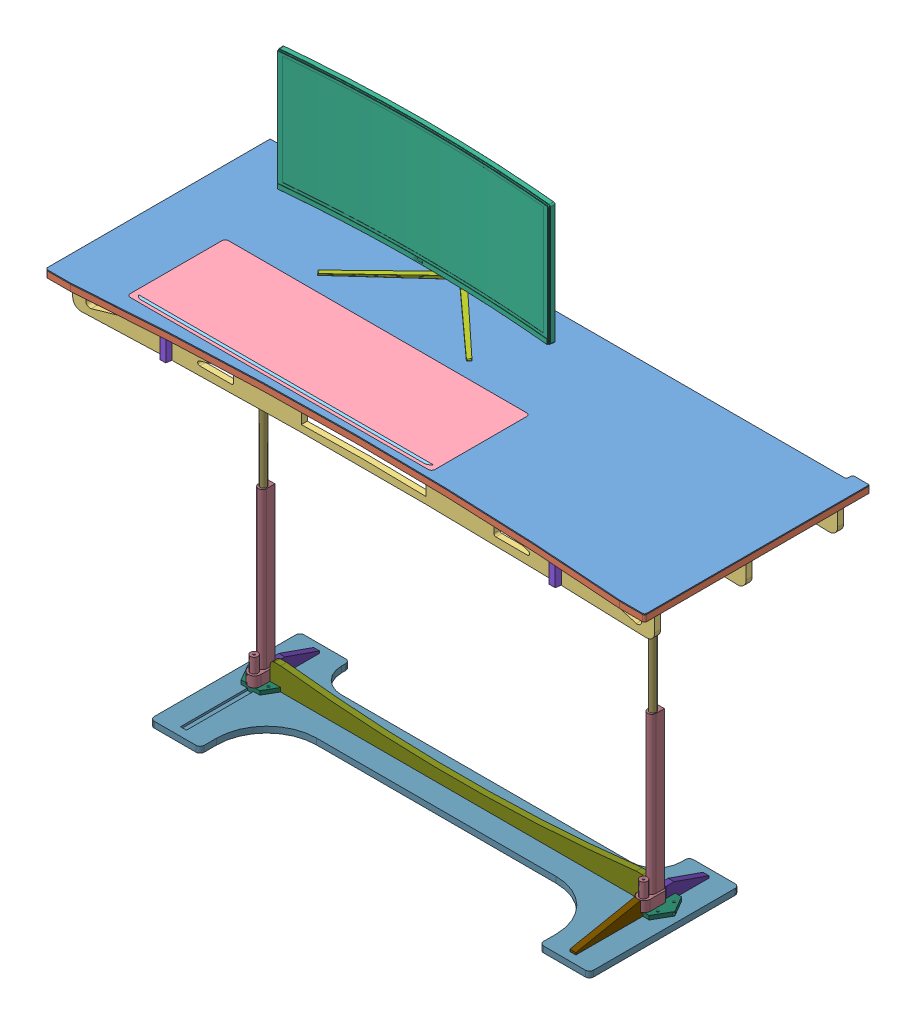
SolidWorks assembly Table2, configuration Default. Lengths in mm.
Overall size (1828.8 1607.28 685.8).
41 component instances, 18 part files, 106 mates.
Components (placement in the parent):
- PlasticDeskSurface-1: PlasticDeskSurface [Default] at (787.903 1218.7548 1407.4946) size (1828.8 3.17 685.8)
- WoodenDeskSurface2-1: WoodenDeskSurface2 [Default] at (787.903 1199.7048 1407.4946) size (1828.8 19.05 685.8)
- TableSupport-1: TableSupport [Default] at (787.268 1155.2548 1683.7196) size (1776.73 100.55 18.29)
- TableSupport-2: TableSupport [Default] at (787.268 1155.2548 1404.3196) size (1776.73 100.55 18.29)
- TableSupport-3: TableSupport [Default] at (787.268 1155.2548 1124.9196) size (1776.73 100.55 18.29)
- CorsairMM200-1: CorsairMM200 [Default] at (533.903 1218.9298 1547.1946) size (930 3 300)
- CorsairMM200Part2-1: CorsairMM200Part2 [Default] at (533.903 1218.9298 1547.1946) size (900 3 10)
- 34monitor-1: 34monitor [Default] at (533.8994 1324.5298 1285.8011) size (858.27 521.12 391.75)
  - Monitor^34monitor-1: Monitor^34monitor [Default] at origin size (858.27 431.15 192.74) (virtual)
  - Stand^34monitor-1: Stand^34monitor [Default] at origin size (475.11 329.67 391.69) (virtual)
- SupportSupport-4: SupportSupport [Default] at (192.8884 1149.35 1407.1136) x (0 0 -1) z (-1 0 0) size (628.27 139.7 18.29)
- SupportSupport-5: SupportSupport [Default] at (1381.6477 1149.35 1407.1136) x (0 0 -1) z (-1 0 0) size (628.27 139.7 18.29)
- LinearActuatorTopSupport-1: LinearActuatorTopSupport [Default] at (192.8884 1060.45 1404.3196) x (0 0 -1) z (-1 0 0) size (152.4 95.25 32.77)
- LinearActuatorTopSupport-2: LinearActuatorTopSupport [Default] at (1381.6477 1060.45 1404.3196) x (0 0 -1) z (-1 0 0) size (152.4 95.25 32.77)
- hex bolt_ai-1: hex bolt_ai [HBOLT 0.2500-20x1.5x0.75-C] at (172.2382 1079.5 1404.3196) x (1 0 0) z (0 0.5 0.866025) size (42.88 12.85 11.13)
- hex bolt_ai-2: hex bolt_ai [HBOLT 0.2500-20x1.5x0.75-C] at (1402.2979 1079.5 1458.2946) x (-1 0 0) z (0 1 0) size (42.88 12.85 11.13)
- hex bolt_ai-3: hex bolt_ai [HBOLT 0.2500-20x1.5x0.75-C] at (172.2382 1079.5 1458.2946) x (1 0 0) z (0 0.5 0.866025) size (42.88 12.85 11.13)
- hex bolt_ai-4: hex bolt_ai [HBOLT 0.2500-20x1.5x0.75-C] at (172.2382 1079.5 1350.3446) x (1 0 0) z (0 0.5 0.866025) size (42.88 12.85 11.13)
- hex bolt_ai-5: hex bolt_ai [HBOLT 0.2500-20x1.5x0.75-C] at (1402.2979 1079.5 1404.3196) x (-1 0 0) z (0 1 0) size (42.88 12.85 11.13)
- hex bolt_ai-6: hex bolt_ai [HBOLT 0.2500-20x1.5x0.75-C] at (1402.2979 1079.5 1350.3446) x (-1 0 0) z (0 1 0) size (42.88 12.85 11.13)
- hex nut_ai-1: hex nut_ai [HNUT 0.2500-20-D-C] at (214.5038 1079.5 1350.3446) x (0 0 -1) z (1 0 0) size (11.11 12.83 5.74)
- hex nut_ai-2: hex nut_ai [HNUT 0.2500-20-D-C] at (1360.0323 1079.5 1350.3446) x (0 0 1) z (-1 0 0) size (11.11 12.83 5.74)
- hex nut_ai-3: hex nut_ai [HNUT 0.2500-20-D-C] at (1360.0323 1079.5 1404.3196) x (0 0 1) z (-1 0 0) size (11.11 12.83 5.74)
- hex nut_ai-4: hex nut_ai [HNUT 0.2500-20-D-C] at (1360.0323 1079.5 1458.2946) x (0 0 1) z (-1 0 0) size (11.11 12.83 5.74)
- hex nut_ai-5: hex nut_ai [HNUT 0.2500-20-D-C] at (214.5038 1079.5 1458.2946) x (0 0 -1) z (1 0 0) size (11.11 12.83 5.74)
- hex nut_ai-6: hex nut_ai [HNUT 0.2500-20-D-C] at (214.5038 1079.5 1404.3196) x (0 0 -1) z (1 0 0) size (11.11 12.83 5.74)
- LinearActuatorRod-1: LinearActuatorRod [Default] at (192.8884 524.51 1404.3196) size (20.07 527.05 20.07)
- hex bolt_ai-12: hex bolt_ai [HBOLT 0.3125-18x1.5x0.875-C] at (171.0444 1041.4 1404.3196) size (44.07 14.66 12.7)
- hex bolt_ai-13: hex bolt_ai [HBOLT 0.3125-18x1.5x0.875-C] at (1359.8037 1041.4 1404.3196) size (44.07 14.66 12.7)
- LinearActuatorRod-2: LinearActuatorRod [Default] at (1381.6477 524.51 1404.3196) size (20.07 527.05 20.07)
- hex nut_ai-7: hex nut_ai [HNUT 0.3125-18-D-C] at (1404.4569 1041.4 1404.3196) x (0 0 -1) z (1 0 0) size (12.7 14.66 6.93)
- hex nut_ai-8: hex nut_ai [HNUT 0.3125-18-D-C] at (215.6976 1041.4 1404.3196) x (0 0 -1) z (1 0 0) size (12.7 14.66 6.93)
- ActuatorBottom-1: ActuatorBottom [Default] at (192.8884 127 1394.7946) size (38.09 527.05 75.55)
- ActuatorBottom-2: ActuatorBottom [Default] at (1381.6477 127 1394.7946) size (38.09 527.05 75.55)
- NewBase1-1: NewBase1 [Default] at (787.2484 96.774 1688.4069) size (1341.12 18.29 457.2)
- NewBase2-1: NewBase2 [Default] at (192.8884 108.712 1394.7946) size (109.02 18.29 98.99)
- NewBase2-2: NewBase2 [Default] at (1381.6084 108.712 1394.7946) x (-1 0 0) z (0 0 -1) size (109.02 18.29 98.99)
- NewBase3-1: NewBase3 [Default] at (787.3031 108.712 1394.7946) size (1148.59 75.44 18.29)
- NewBase4-1: NewBase4 [Default] at (1381.6084 108.712 1345.3013) x (0 0 -1) z (1 0 0) size (131.44 50.04 18.29)
- NewBase4-2: NewBase4 [Default] at (192.8884 108.712 1345.3013) x (0 0 -1) z (1 0 0) size (131.44 50.04 18.29)
- NewBase5-2: NewBase5 [Default] at (1390.7524 108.712 1444.288) x (0 0 1) z (-1 0 0) size (204.47 51.95 18.29)
Mates (geometry in assembly coordinates):
- Coincident4: coincident anti-aligned: plane of PlasticDeskSurface-1 through (-120.147 1218.7548 1744.0446) normal (0 -1 0); plane of WoodenDeskSurface2-1 through (-120.147 1218.7548 1744.0446) normal (0 1 0)
- Coincident5: coincident aligned: plane of PlasticDeskSurface-1 through (1702.303 1221.9298 1744.0446) normal (1 0 0); plane of WoodenDeskSurface2-1 through (1702.303 1218.7548 1744.0446) normal (1 0 0)
- Coincident6: coincident aligned: plane of PlasticDeskSurface-1 through (-69.347 1218.7548 1083.6446) normal (0 0 -1); plane of WoodenDeskSurface2-1 through (-69.347 1199.7048 1083.6446) normal (0 0 -1)
- Coincident7: coincident anti-aligned: plane of WoodenDeskSurface2-1 through (1676.903 1206.0548 1692.8636) normal (0 0 -1); plane of TableSupport-1 through (787.268 -20467.2606 1692.8636) normal (0 0 1)
- Coincident8: coincident anti-aligned: plane of WoodenDeskSurface2-1 through (-101.097 1206.0548 1674.5756) normal (1 0 0); plane of TableSupport-1 through (-101.097 1206.0548 1692.8636) normal (-1 0 0)
- Coincident9: coincident anti-aligned: plane of WoodenDeskSurface2-1 through (787.903 1206.0548 1407.4946) normal (0 -1 0); plane of TableSupport-1 through (-101.097 1206.0548 1692.8636) normal (0 1 0)
- Coincident10: coincident anti-aligned: plane of WoodenDeskSurface2-1 through (1676.903 1206.0548 1413.4636) normal (0 0 -1); plane of TableSupport-2 through (787.268 -20467.2606 1413.4636) normal (0 0 1)
- Coincident11: coincident anti-aligned: plane of WoodenDeskSurface2-1 through (-101.097 1206.0548 1413.4636) normal (1 0 0); plane of TableSupport-2 through (-101.097 1206.0548 1413.4636) normal (-1 0 0)
- Coincident12: coincident anti-aligned: plane of WoodenDeskSurface2-1 through (787.903 1206.0548 1407.4946) normal (0 -1 0); plane of TableSupport-2 through (-101.097 1206.0548 1413.4636) normal (0 1 0)
- Coincident13: coincident anti-aligned: plane of WoodenDeskSurface2-1 through (-101.097 1206.0548 1115.7756) normal (1 0 0); plane of TableSupport-3 through (-101.097 1206.0548 1134.0636) normal (-1 0 0)
- Coincident14: coincident anti-aligned: plane of WoodenDeskSurface2-1 through (1676.903 1206.0548 1115.7756) normal (0 0 1); plane of TableSupport-3 through (787.268 -20467.2606 1115.7756) normal (0 0 -1)
- Coincident15: coincident anti-aligned: plane of WoodenDeskSurface2-1 through (787.903 1206.0548 1407.4946) normal (0 -1 0); plane of TableSupport-3 through (-101.097 1206.0548 1134.0636) normal (0 1 0)
- Parallel1: parallel aligned: plane of TableSupport-1 through (787.268 -20467.2606 1692.8636) normal (0 0 1); plane of assembly through (0 0 0) normal (0 0 1)
- Parallel2: parallel anti-aligned: plane of WoodenDeskSurface2-1 through (-120.147 1199.7048 1744.0446) normal (0 -1 0); plane of assembly through (0 0 0) normal (0 1 0)
- Coincident24: coincident anti-aligned: plane of PlasticDeskSurface-1 through (78.903 1218.9298 1687.1946) normal (0 1 0); plane of CorsairMM200-1 through (78.903 1218.9298 1687.1946) normal (0 -1 0)
- Coincident25: coincident anti-aligned: plane of PlasticDeskSurface-1 through (78.903 1218.9298 1697.1946) normal (0 0 -1); plane of CorsairMM200-1 through (78.903 1221.9298 1697.1946) normal (0 0 1)
- Coincident26: coincident anti-aligned: plane of PlasticDeskSurface-1 through (998.903 1218.9298 1687.1946) normal (-1 0 0); plane of CorsairMM200-1 through (998.903 1221.9298 1687.1946) normal (1 0 0)
- Coincident28: coincident anti-aligned: plane of CorsairMM200-1 through (100.2376 1218.9298 1687.1946) normal (0 0 -1); plane of CorsairMM200Part2-1 through (100.2376 1221.9298 1687.1946) normal (0 0 1)
- Concentric1: concentric anti-aligned: cylinder of CorsairMM200-1 through (964.6509 1218.9298 1664.088) axis (0 1 0) radius 23.29; cylinder of CorsairMM200Part2-1 through (964.6509 1221.9298 1664.088) axis (0 -1 0) radius 23.29
- Coincident29: coincident anti-aligned: plane of PlasticDeskSurface-1 through (78.903 1218.9298 1687.1946) normal (0 1 0); plane of CorsairMM200Part2-1 through (103.1552 1218.9298 1664.088) normal (0 -1 0)
- Coincident30: coincident anti-aligned: plane of PlasticDeskSurface-1 through (-120.147 1221.9298 1744.0446) normal (0 1 0); plane of 34monitor-1/Stand^34monitor-1 through (533.8994 1221.9298 1285.8011) normal (0 -1 0)
- Distance2: distance = 50 mm: point of 34monitor-1/Stand^34monitor-1; line of PlasticDeskSurface-1 through (-69.347 1221.9298 1083.6446) axis (1 0 0)
- Distance3: distance = 660.4 mm: point of 34monitor-1/Stand^34monitor-1; line of PlasticDeskSurface-1 through (-126.497 1221.9298 1064.5946) axis (0 0 1)
- Coincident42: coincident anti-aligned: plane of TableSupport-2 through (183.7444 1114.3023 1413.4636) normal (1 0 0); plane of SupportSupport-4 through (183.7444 1149.35 1407.1136) normal (-1 0 0)
- Perpendicular3: perpendicular: plane of WoodenDeskSurface2-1 through (-120.147 1199.7048 1744.0446) normal (0 -1 0); plane of SupportSupport-4 through (183.7444 1149.35 1407.1136) normal (-1 0 0)
- Coincident44: coincident anti-aligned: plane of TableSupport-1 through (183.7444 1140.206 1692.8636) normal (0 -1 0); plane of SupportSupport-4 through (183.7444 1140.206 1692.8636) normal (0 1 0)
- Coincident45: coincident anti-aligned: plane of TableSupport-1 through (787.268 -20467.2606 1692.8636) normal (0 0 1); plane of SupportSupport-4 through (183.7444 1200.15 1692.8636) normal (0 0 -1)
- Coincident46: coincident anti-aligned: plane of TableSupport-1 through (1390.7917 1114.3023 1692.8636) normal (-1 0 0); plane of SupportSupport-5 through (1390.7917 1149.35 1407.1136) normal (1 0 0)
- Perpendicular4: perpendicular: plane of WoodenDeskSurface2-1 through (-120.147 1199.7048 1744.0446) normal (0 -1 0); plane of SupportSupport-5 through (1390.7917 1149.35 1407.1136) normal (1 0 0)
- Coincident48: coincident anti-aligned: plane of TableSupport-1 through (787.268 -20467.2606 1674.5756) normal (0 0 -1); plane of SupportSupport-5 through (1372.5037 1140.206 1674.5756) normal (0 0 1)
- Coincident49: coincident anti-aligned: plane of TableSupport-1 through (1390.7917 1140.206 1692.8636) normal (0 -1 0); plane of SupportSupport-5 through (1372.5037 1140.206 1692.8636) normal (0 1 0)
- Coincident50: coincident anti-aligned: plane of SupportSupport-4 through (183.7444 1149.35 1407.1136) normal (-1 0 0); plane of LinearActuatorTopSupport-1 through (183.7444 1111.25 1480.5196) normal (1 0 0)
- Coincident51: coincident anti-aligned: plane of SupportSupport-4 through (183.7444 1060.45 1328.1196) normal (0 -1 0); plane of LinearActuatorTopSupport-1 through (192.8884 1060.45 1404.3196) normal (0 1 0)
- Coincident52: coincident anti-aligned: line of SupportSupport-4 through (183.7444 1060.45 1480.5196) axis (1 0 0); line of LinearActuatorTopSupport-1 through (202.0324 1060.45 1480.5196) axis (-1 0 0)
- Coincident53: coincident anti-aligned: plane of SupportSupport-5 through (1372.5037 1149.35 1407.1136) normal (-1 0 0); plane of LinearActuatorTopSupport-2 through (1372.5037 1111.25 1480.5196) normal (1 0 0)
- Coincident54: coincident anti-aligned: plane of SupportSupport-5 through (1372.5037 1060.45 1328.1196) normal (0 -1 0); plane of LinearActuatorTopSupport-2 through (1381.6477 1060.45 1404.3196) normal (0 1 0)
- Coincident55: coincident aligned: line of SupportSupport-5 through (1372.5037 1060.45 1328.1196) axis (1 0 0); line of LinearActuatorTopSupport-2 through (1372.5037 1060.45 1328.1196) axis (1 0 0)
- Concentric2: concentric aligned: cylinder of LinearActuatorTopSupport-1 through (208.7634 1079.5 1350.3446) axis (-1 0 0) radius 3.175; cylinder of hex bolt_ai-4 through (172.2382 1079.5 1350.3446) axis (-1 0 0) radius 3.175
- Coincident56: coincident anti-aligned: plane of LinearActuatorTopSupport-1 through (177.0134 1054.1 1480.5196) normal (-1 0 0); plane of hex bolt_ai-4 through (177.0134 1085.0626 1347.1331) normal (1 0 0)
- Parallel7: parallel anti-aligned: plane of WoodenDeskSurface2-1 through (-120.147 1199.7048 1744.0446) normal (0 -1 0); plane of hex bolt_ai-4 through (177.0134 1085.0626 1347.1331) normal (0 1 0)
- Concentric3: concentric aligned: cylinder of LinearActuatorTopSupport-1 through (208.7634 1079.5 1404.3196) axis (-1 0 0) radius 3.175; cylinder of hex bolt_ai-1 through (172.2382 1079.5 1404.3196) axis (-1 0 0) radius 3.175
- Coincident58: coincident anti-aligned: plane of LinearActuatorTopSupport-1 through (177.0134 1054.1 1480.5196) normal (-1 0 0); plane of hex bolt_ai-1 through (177.0134 1085.0626 1401.1081) normal (1 0 0)
- Parallel8: parallel anti-aligned: plane of WoodenDeskSurface2-1 through (-120.147 1199.7048 1744.0446) normal (0 -1 0); plane of hex bolt_ai-1 through (177.0134 1085.0626 1401.1081) normal (0 1 0)
- Concentric4: concentric aligned: cylinder of LinearActuatorTopSupport-1 through (208.7634 1079.5 1458.2946) axis (-1 0 0) radius 3.175; cylinder of hex bolt_ai-3 through (172.2382 1079.5 1458.2946) axis (-1 0 0) radius 3.175
- Coincident60: coincident anti-aligned: plane of LinearActuatorTopSupport-1 through (177.0134 1054.1 1480.5196) normal (-1 0 0); plane of hex bolt_ai-3 through (177.0134 1085.0626 1455.0831) normal (1 0 0)
- Parallel9: parallel anti-aligned: plane of WoodenDeskSurface2-1 through (-120.147 1199.7048 1744.0446) normal (0 -1 0); plane of hex bolt_ai-3 through (177.0134 1085.0626 1455.0831) normal (0 1 0)
- Concentric5: concentric anti-aligned: cylinder of hex bolt_ai-4 through (172.2382 1079.5 1350.3446) axis (-1 0 0) radius 3.175; cylinder of hex nut_ai-1 through (208.7634 1079.5 1350.3446) axis (1 0 0) radius 2.5527
- Coincident62: coincident anti-aligned: plane of LinearActuatorTopSupport-1 through (208.7634 1054.1 1480.5196) normal (1 0 0); plane of hex nut_ai-1 through (208.7634 1085.9158 1350.3446) normal (-1 0 0)
- Concentric6: concentric anti-aligned: cylinder of hex bolt_ai-1 through (172.2382 1079.5 1404.3196) axis (-1 0 0) radius 3.175; cylinder of hex nut_ai-6 through (208.7634 1079.5 1404.3196) axis (1 0 0) radius 2.5527
- Coincident63: coincident anti-aligned: plane of LinearActuatorTopSupport-1 through (208.7634 1054.1 1480.5196) normal (1 0 0); plane of hex nut_ai-6 through (208.7634 1085.9158 1404.3196) normal (-1 0 0)
- Concentric7: concentric anti-aligned: cylinder of hex bolt_ai-3 through (172.2382 1079.5 1458.2946) axis (-1 0 0) radius 3.175; cylinder of hex nut_ai-5 through (208.7634 1079.5 1458.2946) axis (1 0 0) radius 2.5527
- Coincident64: coincident anti-aligned: plane of LinearActuatorTopSupport-1 through (208.7634 1054.1 1480.5196) normal (1 0 0); plane of hex nut_ai-5 through (208.7634 1085.9158 1458.2946) normal (-1 0 0)
- Concentric8: concentric anti-aligned: cylinder of LinearActuatorTopSupport-2 through (1397.5227 1079.5 1458.2946) axis (-1 0 0) radius 3.175; cylinder of hex bolt_ai-2 through (1402.2979 1079.5 1458.2946) axis (1 0 0) radius 3.175
- Coincident65: coincident anti-aligned: plane of LinearActuatorTopSupport-2 through (1397.5227 1054.1 1480.5196) normal (1 0 0); plane of hex bolt_ai-2 through (1397.5227 1079.5 1464.7178) normal (-1 0 0)
- Parallel10: parallel anti-aligned: plane of WoodenDeskSurface2-1 through (-120.147 1199.7048 1744.0446) normal (0 -1 0); plane of hex bolt_ai-2 through (1397.5227 1085.0626 1461.5062) normal (0 1 0)
- Concentric9: concentric anti-aligned: cylinder of LinearActuatorTopSupport-2 through (1397.5227 1079.5 1404.3196) axis (-1 0 0) radius 3.175; cylinder of hex bolt_ai-5 through (1402.2979 1079.5 1404.3196) axis (1 0 0) radius 3.175
- Coincident67: coincident anti-aligned: plane of LinearActuatorTopSupport-2 through (1397.5227 1054.1 1480.5196) normal (1 0 0); plane of hex bolt_ai-5 through (1397.5227 1079.5 1410.7428) normal (-1 0 0)
- Parallel11: parallel anti-aligned: plane of WoodenDeskSurface2-1 through (-120.147 1199.7048 1744.0446) normal (0 -1 0); plane of hex bolt_ai-5 through (1397.5227 1085.0626 1407.5312) normal (0 1 0)
- Concentric10: concentric anti-aligned: cylinder of LinearActuatorTopSupport-2 through (1397.5227 1079.5 1350.3446) axis (-1 0 0) radius 3.175; cylinder of hex bolt_ai-6 through (1402.2979 1079.5 1350.3446) axis (1 0 0) radius 3.175
- Coincident69: coincident anti-aligned: plane of LinearActuatorTopSupport-2 through (1397.5227 1054.1 1480.5196) normal (1 0 0); plane of hex bolt_ai-6 through (1397.5227 1079.5 1356.7678) normal (-1 0 0)
- Parallel12: parallel anti-aligned: plane of WoodenDeskSurface2-1 through (-120.147 1199.7048 1744.0446) normal (0 -1 0); plane of hex bolt_ai-6 through (1397.5227 1085.0626 1353.5562) normal (0 1 0)
- Concentric11: concentric anti-aligned: cylinder of hex bolt_ai-2 through (1402.2979 1079.5 1458.2946) axis (1 0 0) radius 3.175; cylinder of hex nut_ai-4 through (1365.7727 1079.5 1458.2946) axis (-1 0 0) radius 2.5527
- Coincident71: coincident anti-aligned: plane of LinearActuatorTopSupport-2 through (1365.7727 1054.1 1480.5196) normal (-1 0 0); plane of hex nut_ai-4 through (1365.7727 1085.9158 1458.2946) normal (1 0 0)
- Concentric12: concentric anti-aligned: cylinder of hex bolt_ai-5 through (1402.2979 1079.5 1404.3196) axis (1 0 0) radius 3.175; cylinder of hex nut_ai-3 through (1365.7727 1079.5 1404.3196) axis (-1 0 0) radius 2.5527
- Coincident72: coincident anti-aligned: plane of LinearActuatorTopSupport-2 through (1365.7727 1054.1 1480.5196) normal (-1 0 0); plane of hex nut_ai-3 through (1365.7727 1085.9158 1404.3196) normal (1 0 0)
- Concentric13: concentric anti-aligned: cylinder of hex bolt_ai-6 through (1402.2979 1079.5 1350.3446) axis (1 0 0) radius 3.175; cylinder of hex nut_ai-2 through (1365.7727 1079.5 1350.3446) axis (-1 0 0) radius 2.5527
- Coincident73: coincident anti-aligned: plane of LinearActuatorTopSupport-2 through (1365.7727 1054.1 1480.5196) normal (-1 0 0); plane of hex nut_ai-2 through (1365.7727 1085.9158 1350.3446) normal (1 0 0)
- Concentric14: concentric anti-aligned: cylinder of LinearActuatorTopSupport-1 through (192.8884 1016 1404.3196) axis (0 1 0) radius 10.033; cylinder of LinearActuatorRod-1 through (192.8884 1051.56 1404.3196) axis (0 -1 0) radius 10.033
- Concentric15: concentric aligned: cylinder of LinearActuatorTopSupport-1 through (177.0134 1041.4 1404.3196) axis (1 0 0) radius 3.9688; cylinder of LinearActuatorRod-1 through (182.8554 1041.4 1404.3196) axis (1 0 0) radius 3.9055
- Coincident76: coincident anti-aligned: plane of LinearActuatorTopSupport-1 through (177.0134 1054.1 1480.5196) normal (-1 0 0); plane of hex bolt_ai-12 through (177.0134 1048.7323 1404.3196) normal (1 0 0)
- Concentric18: concentric anti-aligned: cylinder of LinearActuatorTopSupport-1 through (177.0134 1041.4 1404.3196) axis (1 0 0) radius 3.9688; cylinder of hex bolt_ai-12 through (171.0444 1041.4 1404.3196) axis (-1 0 0) radius 3.9688
- Concentric19: concentric anti-aligned: cylinder of LinearActuatorTopSupport-2 through (1381.6477 1016 1404.3196) axis (0 1 0) radius 10.033; cylinder of LinearActuatorRod-2 through (1381.6477 1051.56 1404.3196) axis (0 -1 0) radius 10.033
- Concentric20: concentric aligned: cylinder of LinearActuatorTopSupport-2 through (1365.7727 1041.4 1404.3196) axis (1 0 0) radius 3.9688; cylinder of LinearActuatorRod-2 through (1371.6147 1041.4 1404.3196) axis (1 0 0) radius 3.9055
- Coincident78: coincident anti-aligned: plane of LinearActuatorTopSupport-2 through (1365.7727 1054.1 1480.5196) normal (-1 0 0); plane of hex bolt_ai-13 through (1365.7727 1048.7323 1404.3196) normal (1 0 0)
- Concentric21: concentric anti-aligned: cylinder of LinearActuatorTopSupport-2 through (1365.7727 1041.4 1404.3196) axis (1 0 0) radius 3.9688; cylinder of hex bolt_ai-13 through (1359.8037 1041.4 1404.3196) axis (-1 0 0) radius 3.9688
- Concentric22: concentric anti-aligned: cylinder of hex bolt_ai-13 through (1359.8037 1041.4 1404.3196) axis (-1 0 0) radius 3.9688; cylinder of hex nut_ai-7 through (1397.5227 1041.4 1404.3196) axis (1 0 0) radius 3.2639
- Coincident79: coincident anti-aligned: plane of LinearActuatorTopSupport-2 through (1397.5227 1054.1 1480.5196) normal (1 0 0); plane of hex nut_ai-7 through (1397.5227 1041.4 1417.0196) normal (-1 0 0)
- Concentric23: concentric anti-aligned: cylinder of hex bolt_ai-12 through (171.0444 1041.4 1404.3196) axis (-1 0 0) radius 3.9688; cylinder of hex nut_ai-8 through (208.7634 1041.4 1404.3196) axis (1 0 0) radius 3.2639
- Coincident80: coincident anti-aligned: plane of LinearActuatorTopSupport-1 through (208.7634 1054.1 1480.5196) normal (1 0 0); plane of hex nut_ai-8 through (208.7634 1041.4 1417.0196) normal (-1 0 0)
- Distance4: distance = 381 mm anti-aligned: plane of ActuatorBottom-1 through (192.8884 635 1407.4946) normal (0 1 0); plane of LinearActuatorTopSupport-1 through (192.8884 1016 1404.3196) normal (0 -1 0)
- Distance5: distance = 381 mm anti-aligned: plane of ActuatorBottom-2 through (1381.6477 635 1407.4946) normal (0 1 0); plane of LinearActuatorTopSupport-2 through (1381.6477 1016 1404.3196) normal (0 -1 0)
- Parallel13: parallel aligned: plane of ActuatorBottom-1 through (180.1884 635 1382.0946) normal (0 0 -1); plane of ActuatorBottom-2 through (1368.9477 635 1382.0946) normal (0 0 -1)
- Parallel14: parallel aligned: plane of TableSupport-3 through (787.268 -20467.2606 1115.7756) normal (0 0 -1); plane of ActuatorBottom-1 through (180.1884 635 1382.0946) normal (0 0 -1)
- Concentric26: concentric aligned: cylinder of LinearActuatorRod-1 through (192.8884 1051.56 1404.3196) axis (0 -1 0) radius 10.033; cylinder of ActuatorBottom-1 through (192.8884 635 1404.3196) axis (0 -1 0) radius 10.033
- Concentric27: concentric aligned: cylinder of LinearActuatorRod-2 through (1381.6477 1051.56 1404.3196) axis (0 -1 0) radius 10.033; cylinder of ActuatorBottom-2 through (1381.6477 635 1404.3196) axis (0 -1 0) radius 10.033
- Coincident88: coincident aligned: plane of NewBase1-1 through (189.1326 96.774 1385.6506) normal (0 0 1); plane of NewBase2-1 through (189.1326 127 1385.6506) normal (0 0 1)
- Coincident89: coincident aligned: plane of NewBase1-1 through (183.7444 96.774 1398.5505) normal (1 0 0); plane of NewBase2-1 through (183.7444 127 1398.5505) normal (1 0 0)
- Coincident90: coincident aligned: plane of NewBase1-1 through (1372.4644 96.774 1391.0388) normal (1 0 0); plane of NewBase2-2 through (1372.4644 127 1398.5505) normal (1 0 0)
- Coincident91: coincident anti-aligned: plane of NewBase1-1 through (787.2484 108.712 1688.4069) normal (0 1 0); plane of NewBase2-2 through (1381.6084 108.712 1394.7946) normal (0 -1 0)
- Coincident92: coincident aligned: plane of NewBase1-1 through (1385.3642 96.774 1385.6506) normal (0 0 1); plane of NewBase2-2 through (1377.8526 127 1385.6506) normal (0 0 1)
- Coincident93: coincident anti-aligned: plane of ActuatorBottom-1 through (196.6442 107.95 1385.6506) normal (0 0 -1); plane of NewBase2-1 through (189.1326 127 1385.6506) normal (0 0 1)
- Coincident94: coincident anti-aligned: plane of ActuatorBottom-1 through (183.7444 107.95 1391.0388) normal (-1 0 0); plane of NewBase2-1 through (183.7444 127 1398.5505) normal (1 0 0)
- Coincident95: coincident anti-aligned: plane of ActuatorBottom-1 through (192.8884 127 1407.4946) normal (0 -1 0); plane of NewBase2-1 through (192.8884 127 1394.7946) normal (0 1 0)
- Coincident96: coincident anti-aligned: plane of NewBase1-1 through (787.2484 108.712 1688.4069) normal (0 1 0); plane of NewBase2-1 through (192.8884 108.712 1394.7946) normal (0 -1 0)
- Coincident98: coincident anti-aligned: plane of NewBase1-1 through (244.7591 108.712 1403.9386) normal (0 0 -1); plane of NewBase3-1 through (787.3031 4723.8449 1403.9386) normal (0 0 1)
- Coincident99: coincident anti-aligned: plane of NewBase2-1 through (244.7591 127 1385.6506) normal (1 0 0); plane of NewBase3-1 through (244.7591 108.712 1403.9386) normal (-1 0 0)
- Coincident101: coincident anti-aligned: plane of NewBase1-1 through (1372.4644 108.712 1242.3946) normal (1 0 0); plane of NewBase4-1 through (1372.4644 108.712 1345.3013) normal (-1 0 0)
- Coincident102: coincident anti-aligned: plane of NewBase2-2 through (1410.1834 127 1345.3013) normal (0 0 -1); plane of NewBase4-1 through (1390.7524 127 1345.3013) normal (0 0 1)
- Coincident103: coincident anti-aligned: plane of NewBase1-1 through (787.2484 108.712 1688.4069) normal (0 1 0); plane of NewBase4-1 through (1390.7524 108.712 1345.3013) normal (0 -1 0)
- Coincident104: coincident anti-aligned: plane of NewBase1-1 through (183.7444 108.712 1242.3946) normal (1 0 0); plane of NewBase4-2 through (183.7444 108.712 1345.3013) normal (-1 0 0)
- Coincident105: coincident anti-aligned: plane of NewBase2-1 through (192.8884 127 1394.7946) normal (0 1 0); plane of NewBase4-2 through (202.0324 127 1373.8763) normal (0 -1 0)
- Coincident106: coincident anti-aligned: plane of NewBase2-1 through (221.4634 127 1345.3013) normal (0 0 -1); plane of NewBase4-2 through (202.0324 127 1345.3013) normal (0 0 1)
- Coincident111: coincident anti-aligned: plane of NewBase1-1 through (1372.4644 108.712 1444.288) normal (1 0 0); plane of NewBase5-2 through (1372.4644 132.3125 1444.288) normal (-1 0 0)
- Coincident112: coincident anti-aligned: plane of NewBase2-2 through (1353.0334 127 1444.288) normal (0 0 1); plane of NewBase5-2 through (1372.4644 132.3125 1444.288) normal (0 0 -1)
- Coincident114: coincident anti-aligned: plane of NewBase1-1 through (787.2484 108.712 1688.4069) normal (0 1 0); plane of NewBase3-1 through (244.7591 108.712 1403.9386) normal (0 -1 0)
- Coincident115: coincident anti-aligned: plane of NewBase1-1 through (787.2484 108.712 1688.4069) normal (0 1 0); plane of NewBase5-2 through (1372.4644 108.712 1444.288) normal (0 -1 0)
